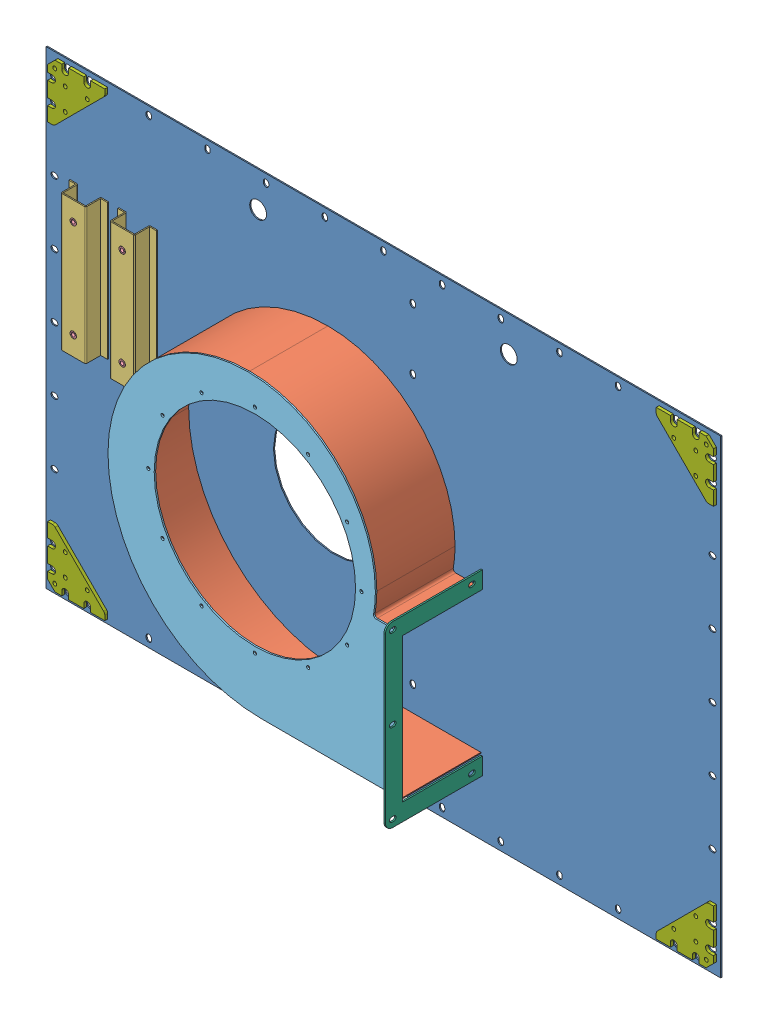
SolidWorks assembly 機體蓋板, configuration 預設. Lengths in mm.
Overall size (1380 960 200.8).
14 component instances, 7 part files, 32 mates.
Components (placement in the parent):
- LB-A54A-02-15-1: LB-A54A-02-15 [預設] at (-80564.8193 24112.8125 -1.15) size (1380 960 2.3)
- LB-A54A-02-16-1: LB-A54A-02-16 [預設] at (-8548.809 -14976.4778 1.15) size (600 601 160)
- LB-A54-08-2-1: LB-A54-08-2 [預設] at (-592.4484 278.8468 34.07) x (0 -1 0) z (0 0 -1) size (278 79.24 32.92)
- LB-A54-08-2-2: LB-A54-08-2 [預設] at (-492.4484 278.8468 34.07) x (0 -1 0) z (0 0 -1) size (278 79.24 32.92)
- 2分半點焊螺帽-1: 2分半點焊螺帽 [預設] at (-659.4484 239.8477 26.57) x (0.122877 -0.992422 0) z (-0.992422 -0.122877 0) size (18.22 7.93 18.22)
- 2分半點焊螺帽-2: 2分半點焊螺帽 [預設] at (-659.4484 39.8477 26.57) x (0.122877 -0.992422 0) z (-0.992422 -0.122877 0) size (18.22 7.93 18.22)
- 2分半點焊螺帽-3: 2分半點焊螺帽 [預設] at (-559.4484 239.8477 26.57) x (1 0 0) z (0 -1 0) size (18.22 7.93 18.22)
- 2分半點焊螺帽-4: 2分半點焊螺帽 [預設] at (-559.4484 39.8477 26.57) x (1 0 0) z (0 -1 0) size (18.22 7.93 18.22)
- LB-A54-08-3-1: LB-A54-08-3 [預設] at (-458.3284 -317.6532 161.15) size (600 601 3)
- LB-A54-08-9-1: LB-A54-08-9 [預設] at (144.6716 9.3468 1.15) x (0 -1 0) z (-1 0 0) size (365 198.5 3)
- LB-A54A-02-31-1: LB-A54A-02-31 [預設] at (-111583.8364 25406.8261 1.15) size (117.04 117.04 6)
- LB-A54A-02-31-2: LB-A54A-02-31 [預設] at (-111583.8364 -25387.1326 7.15) x (1 0 0) z (0 0 -1) size (117.04 117.04 6)
- LB-A54A-02-31-3: LB-A54A-02-31 [預設] at (25549.151 111325.8547 1.15) x (0 -1 0) z (0 0 1) size (117.04 117.04 6)
- LB-A54A-02-31-4: LB-A54A-02-31 [預設] at (111468.1796 -25387.1326 1.15) x (-1 0 0) z (0 0 1) size (117.04 117.04 6)
Mates (geometry in assembly coordinates):
- 重合/共線/共點1: coincident anti-aligned: plane of LB-A54A-02-15-1 through (-747.8284 -470.1532 1.15) normal (0 0 1); plane of LB-A54A-02-16-1 through (89.9364 -18.6532 1.15) normal (0 0 -1)
- 重合/共線/共點2: coincident: line of LB-A54A-02-15-1 through (141.6716 -23.6532 -1.15) axis (-1 0 0); plane of LB-A54A-02-16-1 through (89.9364 -23.6532 161.15) normal (0 1 0)
- 重合/共線/共點4: coincident: line of LB-A54A-02-15-1 through (141.6716 8.1968 -1.15) axis (0 -1 0); plane of LB-A54A-02-16-1 through (141.6716 -23.6532 161.15) normal (1 0 0)
- 重合/共線/共點5: coincident anti-aligned: plane of LB-A54-08-2-1 through (-565.0684 278.8468 1.15) normal (0 0 -1); plane of LB-A54A-02-15-1 through (-747.8284 -470.1532 1.15) normal (0 0 1)
- 重合/共線/共點6: coincident: line of LB-A54A-02-15-1 through (-619.8284 0.8468 -1.15) axis (0 1 0); plane of LB-A54-08-2-1 through (-619.8284 278.8468 1.15) normal (1 0 0)
- 重合/共線/共點7: coincident: line of LB-A54A-02-15-1 through (-619.8284 278.8468 -1.15) axis (-1 0 0); plane of LB-A54-08-2-1 through (-753.8284 278.8468 1.15) normal (0 1 0)
- 重合/共線/共點8: coincident anti-aligned: plane of LB-A54-08-2-2 through (-465.0684 278.8468 1.15) normal (0 0 -1); plane of LB-A54A-02-15-1 through (-747.8284 -470.1532 1.15) normal (0 0 1)
- 重合/共線/共點9: coincident: line of LB-A54A-02-15-1 through (-519.8284 278.8468 -1.15) axis (0 -1 0); plane of LB-A54-08-2-2 through (-519.8284 278.8468 1.15) normal (1 0 0)
- 重合/共線/共點10: coincident: line of LB-A54A-02-15-1 through (-599.8284 278.8468 -1.15) axis (1 0 0); plane of LB-A54-08-2-2 through (-653.8284 278.8468 1.15) normal (0 1 0)
- 同軸心1: concentric aligned: cylinder of LB-A54-08-2-1 through (-659.4484 239.8477 31.77) axis (0 0 1) radius 6.6; cylinder of 2分半點焊螺帽-1 through (-659.4484 239.8477 36.5382) axis (0 0 1) radius 6.5
- 重合/共線/共點11: coincident aligned: plane of LB-A54-08-2-1 through (-592.4484 278.8468 34.07) normal (0 0 1); plane of 2分半點焊螺帽-1 through (-650.3257 240.9772 34.07) normal (0 0 1)
- 同軸心2: concentric aligned: cylinder of 2分半點焊螺帽-3 through (-559.4484 239.8477 36.5382) axis (0 0 1) radius 6.5; cylinder of LB-A54-08-2-2 through (-559.4484 239.8477 31.77) axis (0 0 1) radius 6.6
- 重合/共線/共點12: coincident aligned: plane of LB-A54-08-2-2 through (-492.4484 278.8468 34.07) normal (0 0 1); plane of 2分半點焊螺帽-3 through (-559.4484 249.0401 34.07) normal (0 0 1)
- 重合/共線/共點13: coincident anti-aligned: plane of LB-A54A-02-16-1 through (89.9364 -18.6532 161.15) normal (0 0 1); plane of LB-A54-08-3-1 through (89.9364 -18.6532 161.15) normal (0 0 -1)
- 重合/共線/共點14: coincident aligned: plane of LB-A54A-02-16-1 through (89.9364 -23.6532 161.15) normal (0 1 0); plane of LB-A54-08-3-1 through (141.6716 -23.6532 164.15) normal (0 1 0)
- 重合/共線/共點16: coincident aligned: plane of LB-A54A-02-16-1 through (141.6716 -23.6532 161.15) normal (1 0 0); plane of LB-A54-08-3-1 through (141.6716 -317.6532 164.15) normal (1 0 0)
- 重合/共線/共點17: coincident anti-aligned: plane of LB-A54A-02-16-1 through (141.6716 -23.6532 161.15) normal (1 0 0); plane of LB-A54-08-9-1 through (141.6716 -340.6532 184.65) normal (-1 0 0)
- 重合/共線/共點18: coincident anti-aligned: plane of LB-A54A-02-15-1 through (-747.8284 -470.1532 1.15) normal (0 0 1); plane of LB-A54-08-9-1 through (141.6716 9.3468 1.15) normal (0 0 -1)
- 重合/共線/共點19: coincident: line of LB-A54A-02-16-1 through (141.6716 -25.6532 161.15) axis (0 0 -1); plane of LB-A54-08-9-1 through (141.6716 -25.6532 1.15) normal (0 -1 0)
- 重合/共線/共點20: coincident anti-aligned: plane of LB-A54A-02-15-1 through (-747.8284 -470.1532 1.15) normal (0 0 1); plane of LB-A54A-02-31-1 through (-629.8284 471.1605 1.15) normal (0 0 -1)
- 重合/共線/共點21: coincident: line of LB-A54A-02-15-1 through (-624.1715 465.5036 -1.15) axis (-0.707107 -0.707107 0); plane of LB-A54A-02-31-1 through (-624.1715 465.5036 7.15) normal (0.707107 -0.707107 0)
- 重合/共線/共點23: coincident: line of LB-A54A-02-15-1 through (-621.8284 480.8868 -1.15) axis (-1 0 0); plane of LB-A54A-02-31-1 through (-621.8284 480.8868 7.15) normal (0 1 0)
- 重合/共線/共點24: coincident anti-aligned: plane of LB-A54A-02-15-1 through (-747.8284 -470.1532 1.15) normal (0 0 1); plane of LB-A54A-02-31-2 through (-629.8284 -451.4669 1.15) normal (0 0 -1)
- 重合/共線/共點26: coincident: line of LB-A54A-02-15-1 through (-624.1715 -445.81 -1.15) axis (-0.707107 0.707107 0); plane of LB-A54A-02-31-2 through (-624.1715 -445.81 1.15) normal (0.707107 0.707107 0)
- 重合/共線/共點27: coincident: point of LB-A54A-02-15-1; line of LB-A54A-02-31-2 through (-738.8684 -344.1532 1.15) axis (0 0 1)
- 重合/共線/共點28: coincident anti-aligned: plane of LB-A54A-02-15-1 through (-747.8284 -470.1532 1.15) normal (0 0 1); plane of LB-A54A-02-31-3 through (613.4853 371.8468 1.15) normal (0 0 -1)
- 重合/共線/共點29: coincident: line of LB-A54A-02-15-1 through (508.5148 465.5036 -1.15) axis (0.707107 -0.707107 0); plane of LB-A54A-02-31-3 through (607.8285 366.1899 7.15) normal (-0.707107 -0.707107 0)
- 重合/共線/共點33: coincident: point of LB-A54A-02-15-1; line of LB-A54A-02-31-3 through (506.1716 480.8868 7.15) axis (0 0 -1)
- 重合/共線/共點34: coincident anti-aligned: plane of LB-A54A-02-15-1 through (-747.8284 -470.1532 1.15) normal (0 0 1); plane of LB-A54A-02-31-4 through (514.1716 -451.4669 1.15) normal (0 0 -1)
- 重合/共線/共點35: coincident: line of LB-A54A-02-15-1 through (508.5148 -445.81 -1.15) axis (0.707107 0.707107 0); plane of LB-A54A-02-31-4 through (508.5148 -445.81 7.15) normal (-0.707107 0.707107 0)
- 重合/共線/共點36: coincident: line of LB-A54A-02-15-1 through (623.2116 -373.1532 -1.15) axis (0 1 0); plane of LB-A54A-02-31-4 through (623.2116 -373.1532 7.15) normal (1 0 0)
- 局部直線複製2: unknown: line of LB-A54-08-2-2 through (-582.6084 278.8468 34.07) axis (0 -1 0)
